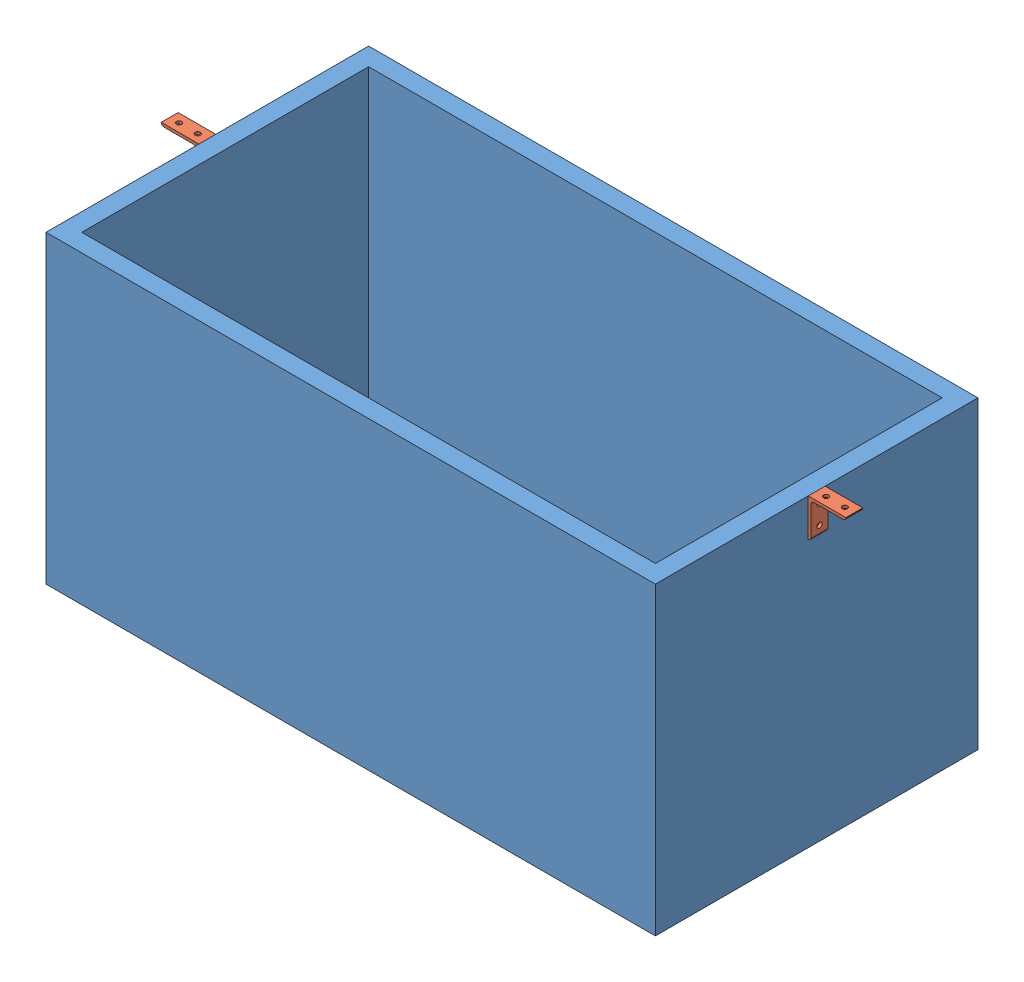
SolidWorks assembly ST_TestBox, configuration Default. Lengths in mm.
Overall size (727.7 323.85 342.9).
3 component instances, 2 part files, 7 mates.
Components (placement in the parent):
- ST_WoodenBox-1: ST_WoodenBox [Default] at origin size (647.7 323.85 342.9)
- MT_CornerBracket_Extended-1: MT_CornerBracket_Extended [5537T441] at (323.85 323.85 0) x (1 0 0) z (0 0 -1) size (40 40 18)
- MT_CornerBracket_Extended-2: MT_CornerBracket_Extended [5537T441] at (-323.85 323.85 0) x (-1 0 0) z (0 0 1) size (40 40 18)
Mates (geometry in assembly coordinates):
- Coincident20: coordinate: point of ST_WoodenBox-1
- Coincident21: coincident anti-aligned: plane of ST_WoodenBox-1 through (323.85 323.85 -171.45) normal (1 0 0); plane of MT_CornerBracket_Extended-1 through (323.85 323.85 -9) normal (-1 0 0)
- Coincident22: coincident aligned: plane of ST_WoodenBox-1 through (0 323.85 0) normal (0 1 0); plane of MT_CornerBracket_Extended-1 through (363.85 323.85 -9) normal (0 1 0)
- Coincident23: coincident anti-aligned: plane of ST_WoodenBox-1 through (0 0 0) normal (0 0 1); plane of MT_CornerBracket_Extended-1 through (323.85 323.85 0) normal (0 0 -1)
- Coincident24: coincident: plane of ST_WoodenBox-1 through (-323.85 323.85 -171.45) normal (-1 0 0); plane of MT_CornerBracket_Extended-2 through (-323.85 323.85 -9) normal (1 0 0)
- Coincident28: coincident: plane of ST_WoodenBox-1 through (0 323.85 0) normal (0 1 0); plane of MT_CornerBracket_Extended-2 through (-363.85 323.85 -9) normal (0 1 0)
- Coincident30: coincident aligned: plane of ST_WoodenBox-1 through (0 0 0) normal (0 0 1); plane of MT_CornerBracket_Extended-2 through (-323.85 323.85 0) normal (0 0 1)
